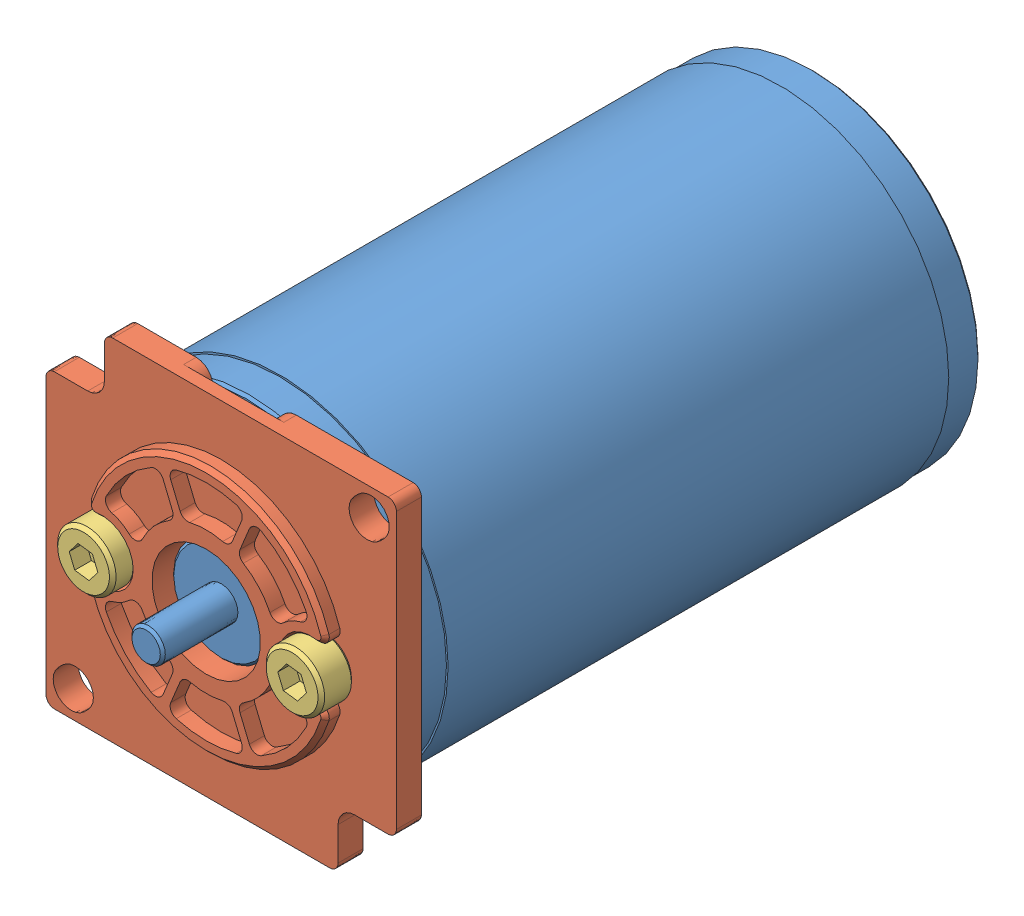
SolidWorks assembly BAG-VersaPlanetaryAssembly, configuration Default. Lengths in mm.
Overall size (42 42 81.5).
4 component instances, 3 part files, 7 mates.
Components (placement in the parent):
- 217-3351-BAG-1: 217-3351-BAG [Default] at (35.8817 39.6648 65.6144) size (40.4 40.4 81.5)
- 550 MOUNTING PLATE-2: 550 MOUNTING PLATE [Default] at (35.8817 39.6648 67.1144) x (0 1 0) z (0 0 -1) size (42 42 4.8)
- SSA_SSAM4-0010ZC-1: SSA_SSAM4-0010ZC [Default] at (23.3817 39.6648 68.6144) x (-0.923728 -0.383049 0) z (-0.383049 0.923728 0) size (7 14 7)
- SSA_SSAM4-0010ZC-2: SSA_SSAM4-0010ZC [Default] at (48.3817 39.6648 68.6144) x (-0.923728 -0.383049 0) z (-0.383049 0.923728 0) size (7 14 7)
Mates (geometry in assembly coordinates):
- Concentric3: concentric: circle of 217-3351-BAG-1; cylinder of 550 MOUNTING PLATE-2 through (35.8817 39.6648 65.6144) axis (0 0 1) radius 6.5
- Concentric4: concentric: cylinder of 217-3351-BAG-1 through (48.3817 39.6648 65.6144) axis (0 0 1) radius 1.65; cylinder of 550 MOUNTING PLATE-2 through (48.3817 39.6648 65.6144) axis (0 0 1) radius 1.6
- Coincident1: coincident: plane of 217-3351-BAG-1 through (35.8817 39.6648 65.6144) normal (0 0 1); plane of 550 MOUNTING PLATE-2 through (35.8817 39.6648 65.6144) normal (0 0 -1)
- Concentric8: concentric: cylinder of 550 MOUNTING PLATE-2 through (23.3817 39.6648 65.6144) axis (0 0 1) radius 1.6; cylinder of SSA_SSAM4-0010ZC-1 through (23.3817 39.6648 58.6144) axis (0 0 1) radius 2
- Coincident4: coincident: plane of 550 MOUNTING PLATE-2 through (35.8817 39.6648 68.6144) normal (0 0 1); plane of SSA_SSAM4-0010ZC-1 through (23.3817 39.6648 68.6144) normal (0 0 -1)
- Concentric9: concentric: cylinder of 550 MOUNTING PLATE-2 through (48.3817 39.6648 65.6144) axis (0 0 1) radius 1.6; cylinder of SSA_SSAM4-0010ZC-2 through (48.3817 39.6648 58.6144) axis (0 0 1) radius 2
- Coincident5: coincident: plane of 550 MOUNTING PLATE-2 through (35.8817 39.6648 68.6144) normal (0 0 1); plane of SSA_SSAM4-0010ZC-2 through (48.3817 39.6648 68.6144) normal (0 0 -1)
